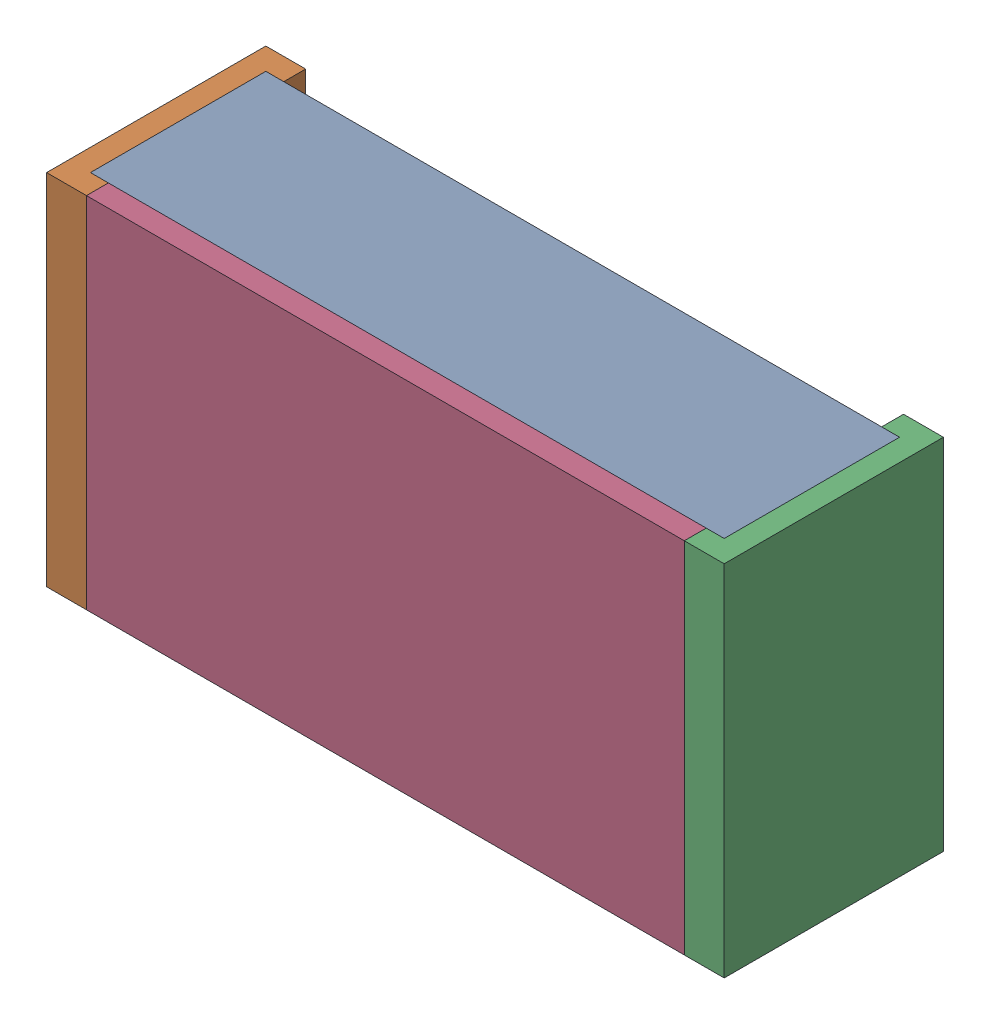
SolidWorks assembly R1, configuration Default. Lengths in mm.
Overall size (1.7 0.9 0.55).
7 component instances, 3 part files, 0 mates.
Components (placement in the parent):
- 6152273536-1: 6152273536 [Default] at (37.2111 -2.2859 0) x (1 0 0) z (0 0 1) size (1.7 0.9 0.55)
  - Mid_Body_3-1: Mid_Body_3 [Default] at (-0.85 -0.45 0) size (1.59 0.9 0.44)
  - Terminal_4-1: Terminal_4 [Default] at (-0.85 -0.45 0) size (0.1 0.9 0.55)
    - Open CASCADE STEP translator 6.8 15.2.1_3-1: Open CASCADE STEP translator 6.8 15.2.1_3 [Default] at origin size (0.1 0.9 0.55)
  - Terminal_4-2: Terminal_4 [Default] at (0.85 0.45 0) x (-1 0 0) z (0 0 1) size (0.1 0.9 0.55)
    - Open CASCADE STEP translator 6.8 15.2.1_3-1: Open CASCADE STEP translator 6.8 15.2.1_3 [Default] at origin size (0.1 0.9 0.55)
  - Mark_3-1: Mark_3 [Default] at (-0.75 -0.45 0.495) size (1.5 0.9 0.06)
